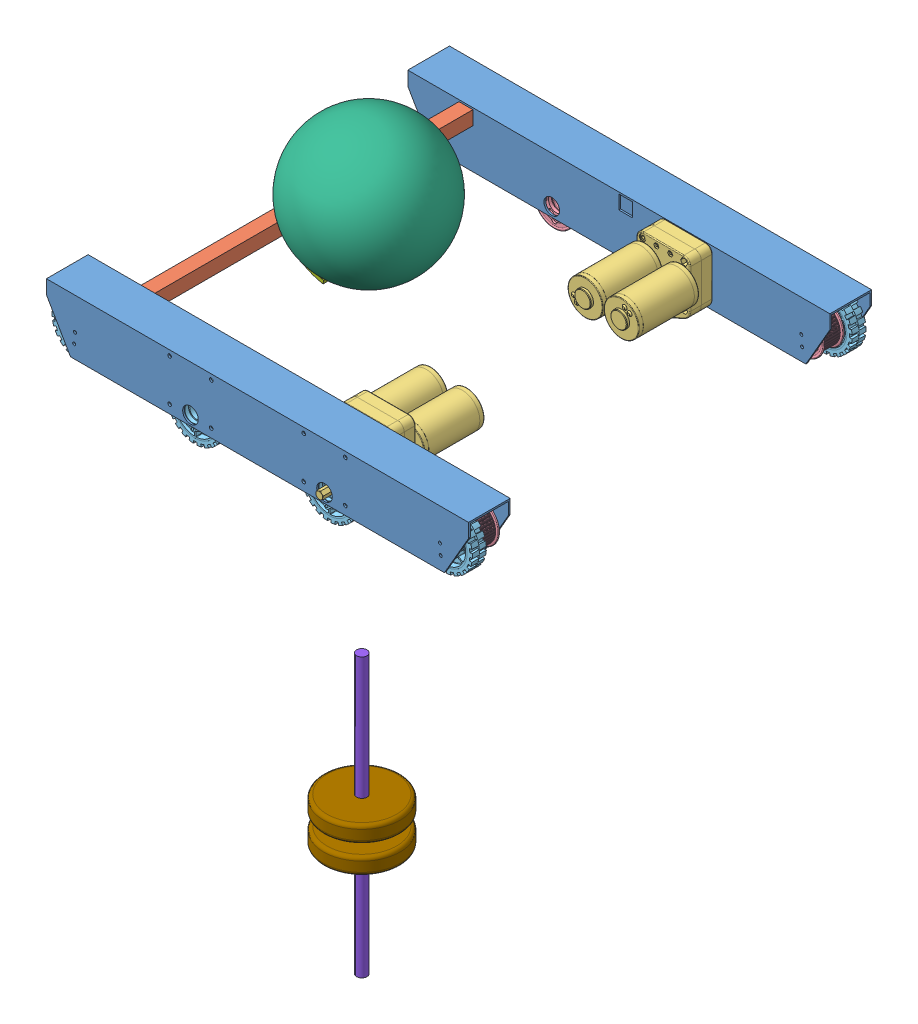
SolidWorks assembly ChassisRamp, configuration Default. Lengths in mm.
Overall size (870.03 778.9 1039.73).
34 component instances, 9 part files, 34 mates.
Components (placement in the parent):
- 3x4x31_C_channel-4: 3x4x31_C_channel [Right C Channel] at (29.6169 80.1221 795.6124) size (771.41 101.6 76.2)
- 3x4x31_C_channel-8: 3x4x31_C_channel [Left C Channel] at (29.6169 80.1221 1456.0124) size (771.41 101.6 76.2)
- 1x1_extrusion-1: 1x1_extrusion [Default] at (-249.7831 115.0471 1125.8124) size (25.4 25.4 730.25)
- Gearbox-1: Gearbox [Default] at (152.1227 81.1565 1397.2749) x (1 -0.00015 0) z (0 0 1) size (141.64 114.27 241.64)
- Gearbox-2: Gearbox [Default] at (152.1227 81.1451 854.3499) x (-1 0.00015 0) z (0 0 -1) size (141.64 114.27 241.64)
- Wheel_Pulley_Asm-1: Wheel_Pulley_Asm [Default] at (89.5414 14.9066 1466.6598) x (0 0 -1) z (1 0 0) size (68.56 101.6 101.6)
  - Double_Wide_Pulley-1: Double_Wide_Pulley [Default] at (-18.9345 -2.473 5.088) size (37.95 74.23 74.23)
  - 4 in HiGrip Wheel-1: 4 in HiGrip Wheel [Default] at (1.9518 29.3543 60.0417) x (1 0 0) z (0 0.000042 1) size (35.12 101.6 101.6)
- Wheel_Pulley_Asm-2: Wheel_Pulley_Asm [Default] at (-155.4594 14.9066 1466.6598) x (0 0 -1) z (1 0 0) size (68.56 101.6 101.6)
  - Double_Wide_Pulley-1: Double_Wide_Pulley [Default] at (-18.9345 -2.473 5.088) size (37.95 74.23 74.23)
  - 4 in HiGrip Wheel-1: 4 in HiGrip Wheel [Default] at (1.9518 29.3543 60.0417) x (1 0 0) z (0 0.000042 1) size (35.12 101.6 101.6)
- Wheel_Pulley_Asm-3: Wheel_Pulley_Asm [Default] at (-366.4348 40.3066 1466.6598) x (0 0 -1) z (1 0 0) size (68.56 101.6 101.6)
  - Double_Wide_Pulley-1: Double_Wide_Pulley [Default] at (-18.9345 -2.473 5.088) size (37.95 74.23 74.23)
  - 4 in HiGrip Wheel-1: 4 in HiGrip Wheel [Default] at (1.9518 29.3543 60.0417) x (1 0 0) z (0 0.000042 1) size (35.12 101.6 101.6)
- Wheel_Pulley_Asm-4: Wheel_Pulley_Asm [Default] at (300.5168 40.3066 1466.6598) x (0 0 -1) z (1 0 0) size (68.56 101.6 101.6)
  - Double_Wide_Pulley-1: Double_Wide_Pulley [Default] at (-18.9345 -2.473 5.088) size (37.95 74.23 74.23)
  - 4 in HiGrip Wheel-1: 4 in HiGrip Wheel [Default] at (1.9518 29.3543 60.0417) x (1 0 0) z (0 0.000042 1) size (35.12 101.6 101.6)
- Wheel_Pulley_Asm-5: Wheel_Pulley_Asm [Default] at (214.6931 14.9066 784.9651) x (0 0 1) z (-1 0 0) size (68.56 101.6 101.6)
  - Double_Wide_Pulley-1: Double_Wide_Pulley [Default] at (-18.9345 -2.473 5.088) size (37.95 74.23 74.23)
  - 4 in HiGrip Wheel-1: 4 in HiGrip Wheel [Default] at (1.9518 29.3543 60.0417) x (1 0 0) z (0 0.000042 1) size (35.12 101.6 101.6)
- Wheel_Pulley_Asm-6: Wheel_Pulley_Asm [Default] at (-30.3076 14.9066 784.9651) x (0 0 1) z (-1 0 0) size (68.56 101.6 101.6)
  - Double_Wide_Pulley-1: Double_Wide_Pulley [Default] at (-18.9345 -2.473 5.088) size (37.95 74.23 74.23)
  - 4 in HiGrip Wheel-1: 4 in HiGrip Wheel [Default] at (1.9518 29.3543 60.0417) x (1 0 0) z (0 0.000042 1) size (35.12 101.6 101.6)
- Wheel_Pulley_Asm-7: Wheel_Pulley_Asm [Default] at (425.6686 40.3066 784.9651) x (0 0 1) z (-1 0 0) size (68.56 101.6 101.6)
  - Double_Wide_Pulley-1: Double_Wide_Pulley [Default] at (-18.9345 -2.473 5.088) size (37.95 74.23 74.23)
  - 4 in HiGrip Wheel-1: 4 in HiGrip Wheel [Default] at (1.9518 29.3543 60.0417) x (1 0 0) z (0 0.000042 1) size (35.12 101.6 101.6)
- Wheel_Pulley_Asm-8: Wheel_Pulley_Asm [Default] at (-241.2831 40.3066 784.9651) x (0 0 1) z (-1 0 0) size (68.56 101.6 101.6)
  - Double_Wide_Pulley-1: Double_Wide_Pulley [Default] at (-18.9345 -2.473 5.088) size (37.95 74.23 74.23)
  - 4 in HiGrip Wheel-1: 4 in HiGrip Wheel [Default] at (1.9518 29.3543 60.0417) x (1 0 0) z (0 0.000042 1) size (35.12 101.6 101.6)
- ball-3580300-1: ball-3580300 [Default] at (-128.2 74.063 1133.0581) size (247.65 247.65 247.65)
- Ramp-1: Ramp [Default] at (-133.2243 189.1456 1125.8124) size (82.86 60.43 127)
- LauncherAxel-1: LauncherAxel [Default] at (444.0958 -203.1906 1717.826) size (19 508 19)
- Wheel-5-1: Wheel-5 [Default] at (444.0958 -188.2168 1717.826) size (139.7 30.48 139.7)
- Wheel-5-2: Wheel-5 [Default] at (444.0958 -238.5029 1717.826) size (139.7 30.48 139.7)
Mates (geometry in assembly coordinates):
- Concentric3: concentric aligned: cylinder of 3x4x31_C_channel-4 through (-249.7831 115.0471 691.9804) axis (0 0 1) radius 2.0828; cylinder of 1x1_extrusion-1 through (-249.7831 115.0471 678.6454) axis (0 0 1) radius 2.0828
- Coincident2: coincident anti-aligned: plane of 3x4x31_C_channel-4 through (415.3226 127.7471 830.5374) normal (0 -1 0); plane of 1x1_extrusion-1 through (-262.4831 127.7471 1490.9374) normal (0 1 0)
- Concentric4: concentric aligned: cylinder of 3x4x31_C_channel-8 through (-249.7831 115.0471 1352.3804) axis (0 0 1) radius 2.0828; cylinder of 1x1_extrusion-1 through (-249.7831 115.0471 678.6454) axis (0 0 1) radius 2.0828
- Coincident3: coincident anti-aligned: plane of 3x4x31_C_channel-8 through (415.3226 127.7471 1490.9374) normal (0 0 -1); plane of 1x1_extrusion-1 through (-249.7831 115.0471 1490.9374) normal (0 0 1)
- Coincident4: coincident anti-aligned: plane of 3x4x31_C_channel-8 through (415.3226 127.7471 1490.9374) normal (0 -1 0); plane of 1x1_extrusion-1 through (-262.4831 127.7471 1490.9374) normal (0 1 0)
- Concentric6: concentric aligned: cylinder of 3x4x31_C_channel-4 through (-249.7831 115.0471 691.9804) axis (0 0 1) radius 2.0828; cylinder of 1x1_extrusion-1 through (-249.7831 115.0471 678.6454) axis (0 0 1) radius 2.0828
- Coincident9: coincident anti-aligned: plane of 3x4x31_C_channel-4 through (415.3226 127.7471 760.6874) normal (0 0 1); plane of 1x1_extrusion-1 through (-249.7831 115.0471 760.6874) normal (0 0 -1)
- Coincident10: coincident anti-aligned: plane of 3x4x31_C_channel-4 through (415.3226 127.7471 830.5374) normal (0 -1 0); plane of 1x1_extrusion-1 through (-262.4831 127.7471 1490.9374) normal (0 1 0)
- Coincident13: coincident anti-aligned: plane of 3x4x31_C_channel-4 through (415.3226 130.9221 833.7124) normal (0 0 1); plane of Gearbox-2 through (121.6377 47.6842 833.7124) normal (0 0 -1)
- Distance1: distance = 0.7153 mm anti-aligned: plane of 3x4x31_C_channel-8 through (415.3226 127.7471 1490.9374) normal (0 0 -1); plane of Wheel_Pulley_Asm-1/4 in HiGrip Wheel-1 through (152.1173 46.7846 1490.2222) normal (0 0 1)
- Concentric13: concentric anti-aligned: cylinder of 3x4x31_C_channel-8 through (-92.8835 46.7846 1352.3804) axis (0 0 1) radius 14.2875; cylinder of Wheel_Pulley_Asm-2/4 in HiGrip Wheel-1 through (-92.8835 46.7846 1490.2222) axis (0 0 -1) radius 12.2174
- Distance2: distance = 0.7153 mm anti-aligned: plane of Wheel_Pulley_Asm-2/4 in HiGrip Wheel-1 through (-92.8835 46.7846 1490.2222) normal (0 0 1); plane of 3x4x31_C_channel-8 through (415.3226 127.7471 1490.9374) normal (0 0 -1)
- Concentric14: concentric anti-aligned: cylinder of 3x4x31_C_channel-8 through (-303.859 72.1846 1352.3804) axis (0 0 1) radius 2.75; cylinder of Wheel_Pulley_Asm-3/4 in HiGrip Wheel-1 through (-303.859 72.1846 1490.2222) axis (0 0 -1) radius 12.2174
- Distance3: distance = 0.7153 mm anti-aligned: plane of Wheel_Pulley_Asm-3/4 in HiGrip Wheel-1 through (-303.859 72.1846 1490.2222) normal (0 0 1); plane of 3x4x31_C_channel-8 through (415.3226 127.7471 1490.9374) normal (0 0 -1)
- Concentric15: concentric aligned: cylinder of 3x4x31_C_channel-8 through (152.1173 46.7846 1352.3804) axis (0 0 1) radius 14.2875; cylinder of Wheel_Pulley_Asm-1/4 in HiGrip Wheel-1 through (152.1173 46.7846 1483.2372) axis (0 0 1) radius 14.2875
- Coincident17: coincident anti-aligned: plane of 3x4x31_C_channel-8 through (415.3226 130.9221 1417.9124) normal (0 0 -1); plane of Gearbox-1 through (182.5977 47.6865 1417.9124) normal (0 0 1)
- Concentric19: concentric anti-aligned: cylinder of 3x4x31_C_channel-8 through (363.0927 72.1846 1352.3804) axis (0 0 1) radius 2.75; cylinder of Wheel_Pulley_Asm-4/4 in HiGrip Wheel-1 through (363.0927 72.1846 1490.2222) axis (0 0 -1) radius 12.2174
- Distance4: distance = 0.7153 mm anti-aligned: plane of Wheel_Pulley_Asm-4/4 in HiGrip Wheel-1 through (363.0927 72.1846 1490.2222) normal (0 0 1); plane of 3x4x31_C_channel-8 through (415.3226 127.7471 1490.9374) normal (0 0 -1)
- Concentric20: concentric aligned: cylinder of 3x4x31_C_channel-4 through (152.1173 46.7846 691.9804) axis (0 0 1) radius 14.2875; cylinder of Wheel_Pulley_Asm-5/4 in HiGrip Wheel-1 through (152.1173 46.7846 761.4027) axis (0 0 1) radius 12.2174
- Distance5: distance = 0.7153 mm anti-aligned: plane of Wheel_Pulley_Asm-5/4 in HiGrip Wheel-1 through (152.1173 46.7846 761.4027) normal (0 0 -1); plane of 3x4x31_C_channel-4 through (415.3226 127.7471 760.6874) normal (0 0 1)
- Concentric21: concentric aligned: cylinder of 3x4x31_C_channel-4 through (-92.8835 46.7846 691.9804) axis (0 0 1) radius 14.2875; cylinder of Wheel_Pulley_Asm-6/4 in HiGrip Wheel-1 through (-92.8835 46.7846 761.4027) axis (0 0 1) radius 12.2174
- Distance6: distance = 0.7153 mm anti-aligned: plane of Wheel_Pulley_Asm-6/4 in HiGrip Wheel-1 through (-92.8835 46.7846 761.4027) normal (0 0 -1); plane of 3x4x31_C_channel-4 through (415.3226 127.7471 760.6874) normal (0 0 1)
- Concentric22: concentric aligned: cylinder of 3x4x31_C_channel-4 through (363.0927 72.1846 691.9804) axis (0 0 1) radius 2.75; cylinder of Wheel_Pulley_Asm-7/4 in HiGrip Wheel-1 through (363.0927 72.1846 761.4027) axis (0 0 1) radius 12.2174
- Distance7: distance = 0.7153 mm anti-aligned: plane of Wheel_Pulley_Asm-7/4 in HiGrip Wheel-1 through (363.0927 72.1846 761.4027) normal (0 0 -1); plane of 3x4x31_C_channel-4 through (415.3226 127.7471 760.6874) normal (0 0 1)
- Concentric23: concentric aligned: cylinder of 3x4x31_C_channel-4 through (-303.859 72.1846 691.9804) axis (0 0 1) radius 2.75; cylinder of Wheel_Pulley_Asm-8/4 in HiGrip Wheel-1 through (-303.859 72.1846 761.4027) axis (0 0 1) radius 12.2174
- Distance8: distance = 0.7153 mm anti-aligned: plane of Wheel_Pulley_Asm-8/4 in HiGrip Wheel-1 through (-303.859 72.1846 761.4027) normal (0 0 -1); plane of 3x4x31_C_channel-4 through (415.3226 127.7471 760.6874) normal (0 0 1)
- Concentric24: concentric aligned: cylinder of 3x4x31_C_channel-8 through (190.2287 121.1986 1494.1124) axis (0 0 -1) radius 3.302; cylinder of Gearbox-1 through (190.2287 121.1986 1385.5274) axis (0 0 -1) radius 2.5146
- Concentric25: concentric aligned: cylinder of 3x4x31_C_channel-8 through (190.2173 44.9986 1494.1124) axis (0 0 -1) radius 3.302; cylinder of Gearbox-1 through (190.2173 44.9986 1385.5274) axis (0 0 -1) radius 2.5146
- Concentric26: concentric aligned: cylinder of 3x4x31_C_channel-4 through (114.0287 121.1986 800.4688) axis (0 0 1) radius 3.302; cylinder of Gearbox-2 through (114.0287 121.1986 866.0974) axis (0 0 1) radius 2.5146
- Concentric27: concentric aligned: cylinder of 3x4x31_C_channel-4 through (114.0173 44.9986 800.4688) axis (0 0 1) radius 3.302; cylinder of Gearbox-2 through (114.0173 44.9986 866.0974) axis (0 0 1) radius 2.5146
- Coincident26: coincident aligned: plane of 1x1_extrusion-1 through (-249.7831 115.0471 1125.8124) normal (0 0 1); plane of Ramp-1 through (-133.2243 189.1456 1125.8124) normal (0 0 1)
- Coincident27: coincident aligned: line of 1x1_extrusion-1 through (-237.0831 127.7471 1490.9374) axis (0 0 -1); line of Ramp-1 through (-237.0831 127.7471 1189.3124) axis (0 0 -1)
- Concentric28: concentric anti-aligned: cylinder of LauncherAxel-1 through (444.0958 50.8094 1717.826) axis (0 -1 0) radius 9.4996; cylinder of Wheel-5-2 through (444.0958 -253.7429 1717.826) axis (0 1 0) radius 4.7625
- Concentric29: concentric anti-aligned: cylinder of LauncherAxel-1 through (444.0958 50.8094 1717.826) axis (0 -1 0) radius 9.4996; cylinder of Wheel-5-1 through (444.0958 -203.4568 1717.826) axis (0 1 0) radius 4.7625
